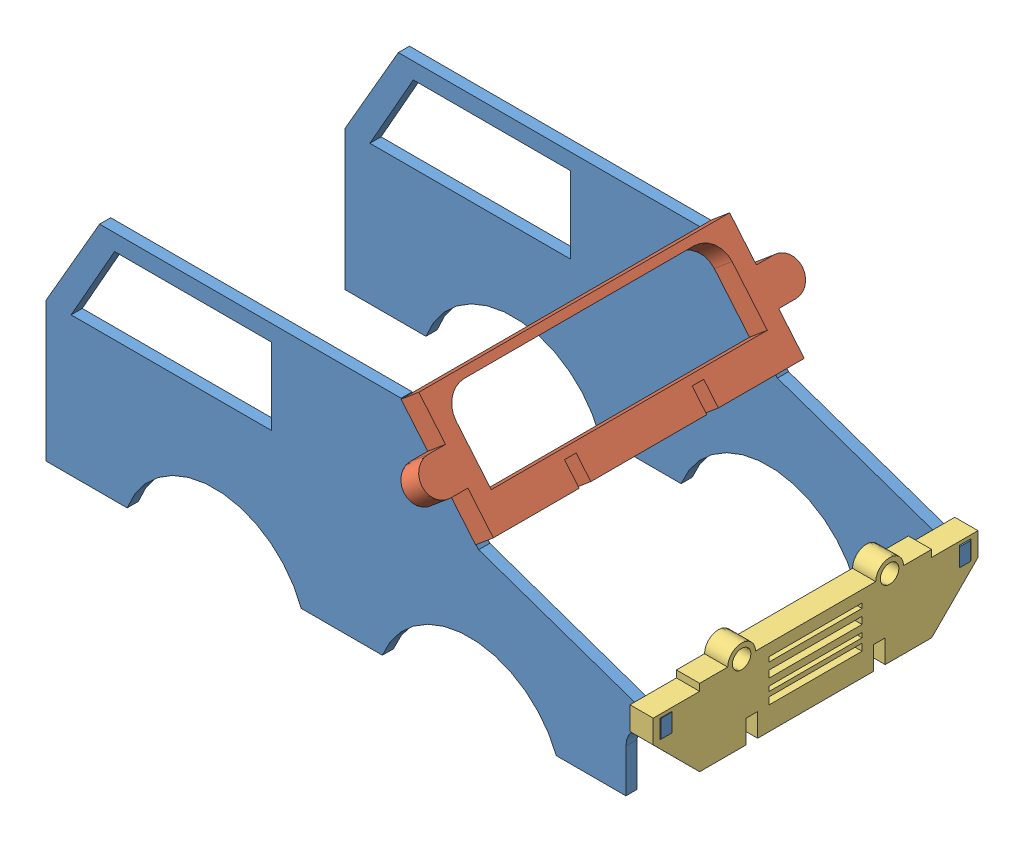
SolidWorks assembly CarroAlan, configuration Predeterminado. Lengths in mm.
Overall size (265.01 106.43 164).
5 component instances, 4 part files, 3 mates.
Components (placement in the parent):
- LateralAlan-1: LateralAlan [Predeterminado] at (-8.8589 -71.3997 258.1976) size (265.01 100 4.8)
- ParabrisasAlan-1: ParabrisasAlan [Predeterminado] at (56.5349 -3.274 324.8244) x (0 0 1) z (-0.766044 -0.642788 0) size (164 50 10)
- ParrillaAlan-1: ParrillaAlan [Predeterminado] at (118.6217 -62.966 324.9976) x (0 0 -1) z (1 0 0) size (140 39.02 10)
- Pieza2^CarroAlan-1: Pieza2^CarroAlan [Predeterminado] at (-8.8589 -71.3997 258.1976) x (-1 0 0) z (0 0 -1) (virtual)
- LateralAlan-3: LateralAlan [Predeterminado] at (-8.8589 -71.0654 386.9855) size (265.01 100 4.8)
Mates (geometry in assembly coordinates):
- Coincidente1: coincident anti-aligned: plane of LateralAlan-1 through (-8.8589 -71.3997 262.9976) normal (0 0 1); plane of ParrillaAlan-1 through (128.6217 -62.966 262.9976) normal (0 0 -1)
- Coincidente5: coincident anti-aligned: plane of LateralAlan-1 through (55.4007 -17.4795 262.9976) normal (0.766044 0.642788 0); plane of ParabrisasAlan-1 through (48.8745 -9.7019 324.8244) normal (-0.766044 -0.642788 0)
- Coincidente9: coincident anti-aligned: line of LateralAlan-1 through (16.7351 28.6003 262.9976) axis (0 0 -1); line of ParabrisasAlan-1 through (16.7351 28.6003 257.8244) axis (0 0 1)
